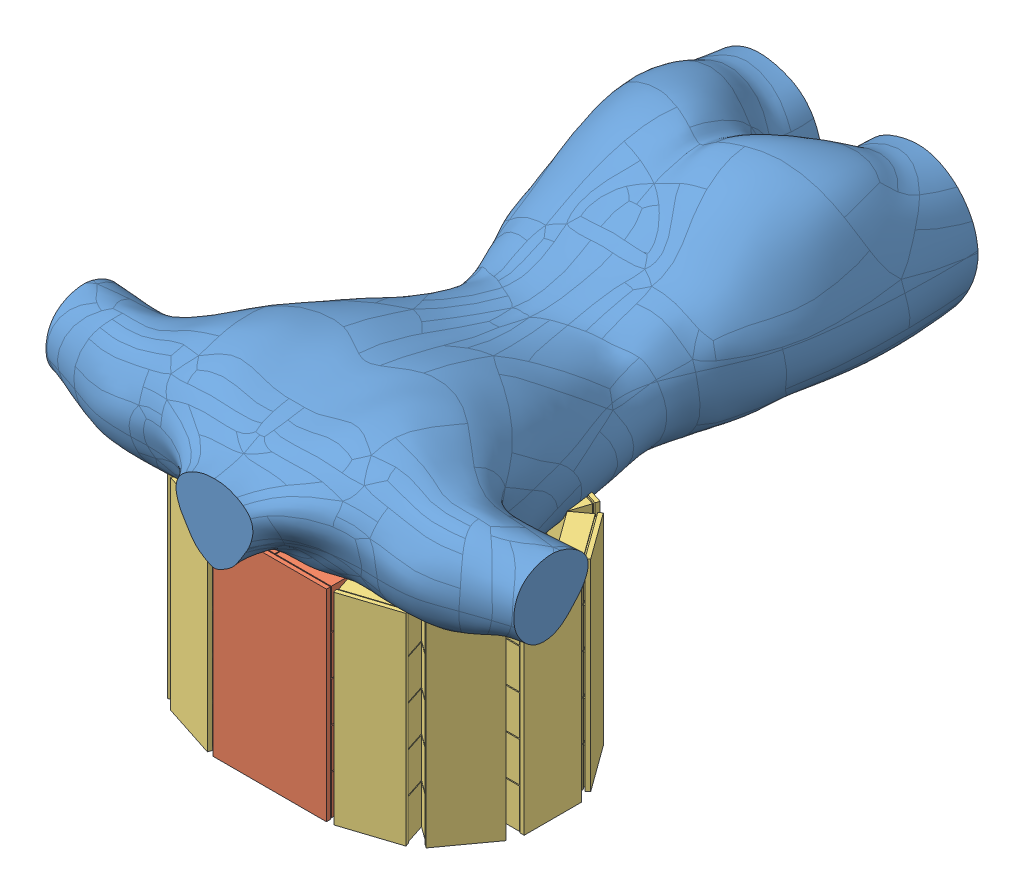
SolidWorks assembly BODYassembly, configuration Default. Lengths in mm.
Overall size (637.83 446.02 817.55).
16 component instances, 3 part files, 0 mates.
Components (placement in the parent):
- woman body-1: woman body [Default] at (378.1985 468.055 204.3879) size (637.83 301.02 817.55)
- Detector1-1: Detector1 [Default] at (227.463 89.1984 1006.0827) x (1 0 0) z (0 1 0) size (495.24 340.33 250)
  - top_bottomDetector-1: top_bottomDetector [Default] at (86.8452 103.3776 184.3748) size (141 32 250)
  - CshapedDetector-1: CshapedDetector [Default] at (185.8864 -33.4141 0.115) x (0.951057 0.309017 0) z (0 0 1) size (177.89 270.84 250)
    - 1Detector-1: 1Detector [Default] at (91.8512 126.8436 184.2598) size (71 32 250)
    - 1Detector-2: 1Detector [Default] at (173.0714 153.2337 184.2598) x (0.809017 0.587785 0) z (0 0 1) size (71 32 250)
    - 1Detector-4: 1Detector [Default] at (223.2683 222.3237 184.2598) x (0.309017 0.951057 0) z (0 0 1) size (71 32 250)
    - 1Detector-5: 1Detector [Default] at (223.2683 307.7237 184.2598) x (-0.309017 0.951057 0) z (0 0 1) size (71 32 250)
    - 1Detector-6: 1Detector [Default] at (173.0714 376.8138 184.2598) x (-0.809017 0.587785 0) z (0 0 1) size (71 32 250)
  - CshapedDetector-2: CshapedDetector [Default] at (57.8041 527.4581 0.115) x (-0.951057 -0.309017 0) z (0 0 1) size (177.89 270.84 250)
    - 1Detector-1: 1Detector [Default] at (91.8512 126.8436 184.2598) size (71 32 250)
    - 1Detector-2: 1Detector [Default] at (173.0714 153.2337 184.2598) x (0.809017 0.587785 0) z (0 0 1) size (71 32 250)
    - 1Detector-4: 1Detector [Default] at (223.2683 222.3237 184.2598) x (0.309017 0.951057 0) z (0 0 1) size (71 32 250)
    - 1Detector-5: 1Detector [Default] at (223.2683 307.7237 184.2598) x (-0.309017 0.951057 0) z (0 0 1) size (71 32 250)
    - 1Detector-6: 1Detector [Default] at (173.0714 376.8138 184.2598) x (-0.809017 0.587785 0) z (0 0 1) size (71 32 250)
  - top_bottomDetector-2: top_bottomDetector [Default] at (156.8452 390.6663 184.3748) x (-1 0 0) z (0 0 1) size (141 32 250)
